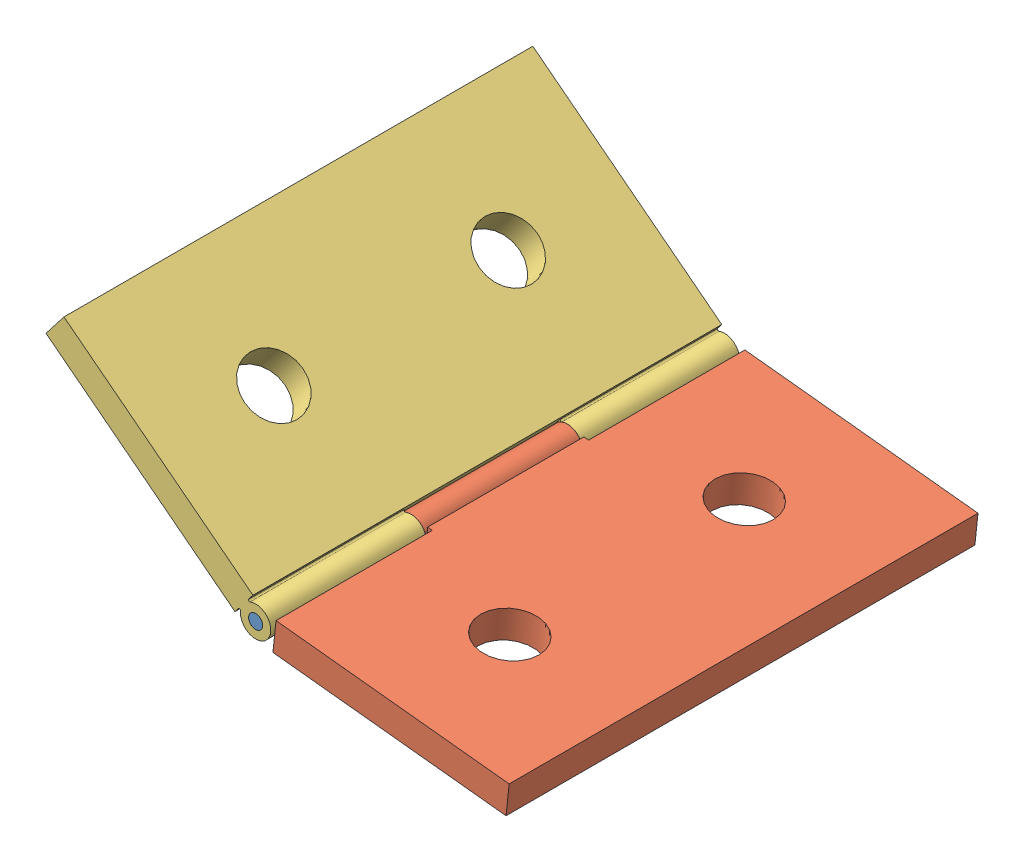
SolidWorks assembly ESAMBLAJE, configuration Predeterminado. Lengths in mm.
Overall size (50.37 22.76 50.9).
3 component instances, 3 part files, 4 mates.
Components (placement in the parent):
- tornillo 3-1: tornillo 3 [Predeterminado] at (-0.1124 -0.1798 -25.4) size (1.52 1.52 50.8)
- Placa 1-1: Placa 1 [Predeterminado] at (14.8242 -0.2436 0.0961) x (0 0 1) z (0.994353 -0.106126 0) size (50.8 3.3 29.21)
- placa 2-1: placa 2 [Predeterminado] at (-12.7879 7.722 0) x (0 0 1) z (-0.790304 0.612716 0) size (50.8 3.3 29.21)
Mates (geometry in assembly coordinates):
- Concéntrica1: concentric anti-aligned: cylinder of tornillo 3-1 through (-0.1124 -0.1798 25.4) axis (0 0 -1) radius 0.762; cylinder of Placa 1-1 through (-0.1124 -0.1798 -8.3706) axis (0 0 1) radius 0.762
- Concéntrica2: concentric anti-aligned: cylinder of tornillo 3-1 through (-0.1124 -0.1798 25.4) axis (0 0 -1) radius 0.762; cylinder of placa 2-1 through (-0.1124 -0.1798 -8.4667) axis (0 0 1) radius 0.762
- Coincidente2: coincident aligned: plane of Placa 1-1 through (1.5002 0.5691 -8.3706) normal (0 0 -1); circle of placa 2-1
- Coincidente3: coincident aligned: plane of tornillo 3-1 through (-0.1124 -0.1798 -25.4) normal (0 0 -1); plane of placa 2-1 through (-20.8793 18.0127 -25.4) normal (0 0 -1)
